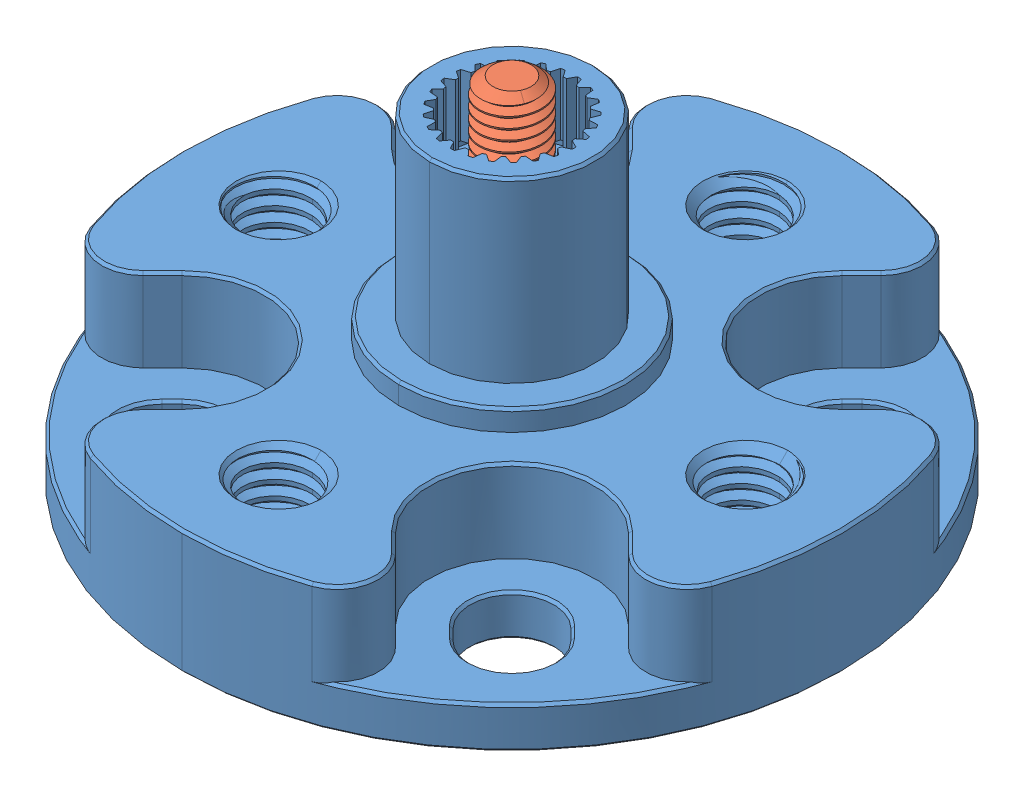
SolidWorks assembly Servo Hub-Shaft (25 Tooth, 8mm Shaft Diameter, 16mm Length) 1910-0025-0816, configuration Default. Lengths in mm.
Overall size (32 17.1 32).
2 component instances, 2 part files, 0 mates.
Components (placement in the parent):
- 1910-0025-0816.STEP-1: 1910-0025-0816.STEP [Default] at (-26.5689 7.4772 3.7047) size (32 15.6 32)
- 2800-0003-0012.STEP-1: 2800-0003-0012.STEP [Default] at (-26.5689 24.5772 3.7047) x (0.895056 0 0.445953) z (0 1 0) size (5.5 5.5 15.01)
